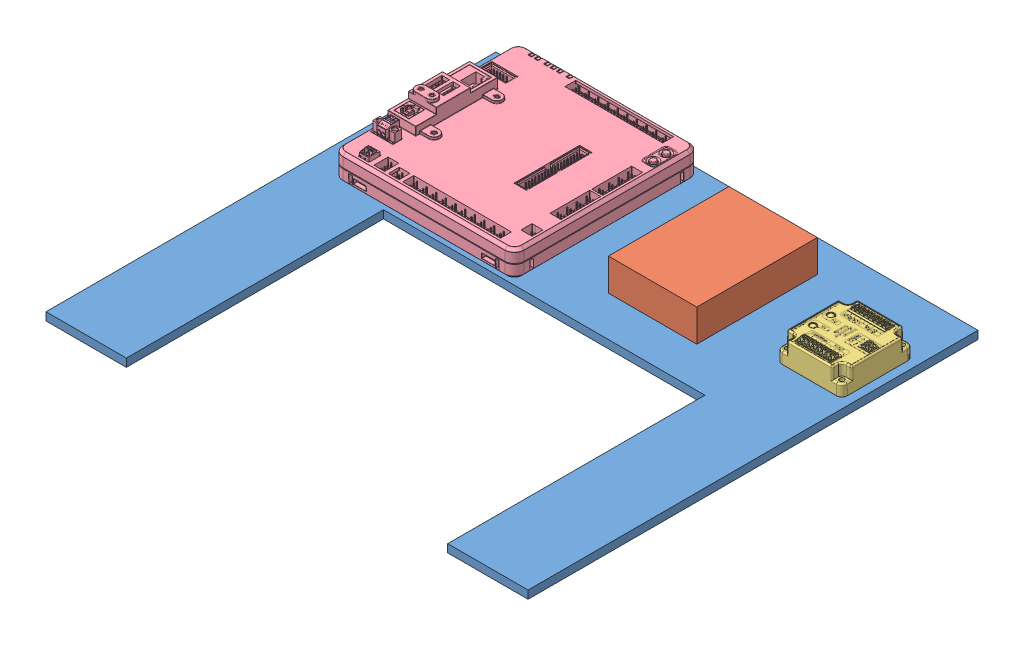
SolidWorks assembly bottom board assem, configuration Default. Lengths in mm.
Overall size (381 43.11 355.6).
4 component instances, 4 part files, 11 mates.
Components (placement in the parent):
- bottom board-1: bottom board [Default] at (-48.016 157.2919 569.8303) size (381 6.35 355.6)
- radio b;ock-1: radio b;ock [Default] at (161.534 163.6419 261.2203) size (69.85 25.4 95.25)
- VRM-1: VRM [Default] at (298.4411 170.7478 212.5635) x (0 0 -1) z (1 0 0) size (56.39 19.92 51.56)
- Roborio-1: Roborio [Default] at (45.7952 173.2939 218.2359) x (0 0 -1) z (0 1 0) size (146.27 143.19 36.83)
Mates (geometry in assembly coordinates):
- Coincident1: coincident anti-aligned: plane of bottom board-1 through (-48.016 163.6419 569.8303) normal (0 1 0); plane of radio b;ock-1 through (161.534 163.6419 261.2203) normal (0 -1 0)
- Distance1: distance = 25.4 mm aligned: plane of radio b;ock-1 through (161.534 189.0419 165.9703) normal (0 0 -1); plane of bottom board-1 through (-48.016 163.6419 140.5703) normal (0 0 -1)
- Distance2: distance = 101.6 mm aligned: plane of radio b;ock-1 through (231.384 189.0419 261.2203) normal (1 0 0); plane of bottom board-1 through (332.984 163.6419 569.8303) normal (1 0 0)
- Coincident4: coincident anti-aligned: plane of bottom board-1 through (-48.016 163.6419 569.8303) normal (0 1 0); plane of VRM-1 through (278.8939 163.6419 189.2191) normal (0 -1 0)
- Parallel1: parallel aligned: plane of bottom board-1 through (332.984 163.6419 569.8303) normal (1 0 0); plane of VRM-1 through (319.6883 183.5411 216.1904) normal (1 0 0)
- Distance4: distance = 19.05 mm: line of bottom board-1 through (332.984 163.6419 496.1703) axis (0 0 -1); plane of VRM-1 through (313.934 183.5411 194.4503) normal (1 0 0)
- Distance5: distance = 50.8 mm aligned: plane of bottom board-1 through (-48.016 163.6419 140.5703) normal (0 0 -1); plane of VRM-1 through (296.434 183.5411 191.3703) normal (0 0 -1)
- Coincident9: coincident: plane of bottom board-1 through (-48.016 163.6419 569.8303) normal (0 1 0); plane of Roborio-1 through (117.7619 163.6419 293.5162) normal (0 1 0)
- Perpendicular1: perpendicular: plane of bottom board-1 through (-48.016 163.6419 569.8303) normal (-1 0 0); plane of Roborio-1 through (-16.9786 192.0773 267.6794) normal (0 0 -1)
- Distance7: distance = 38.1 mm: plane of bottom board-1 through (-48.016 163.6419 569.8303) normal (-1 0 0); plane of Roborio-1 through (-9.916 187.8973 286.859) normal (1 0 0)
- Distance9: distance = 12.7 mm aligned: plane of Roborio-1 through (27.8394 183.6613 153.2703) normal (0 0 -1); plane of bottom board-1 through (-48.016 163.6419 140.5703) normal (0 0 -1)
